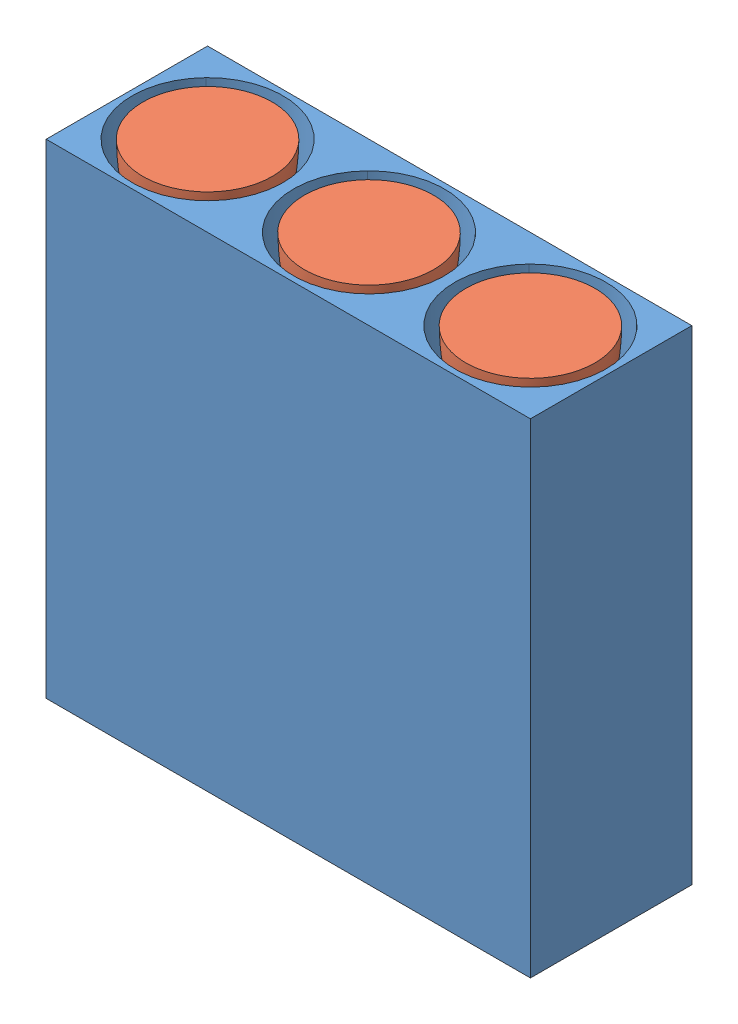
SolidWorks assembly WiderSpace, configuration Default. Lengths in mm.
Overall size (15.49 15 5.52).
4 component instances, 2 part files, 1 mates.
Components (placement in the parent):
- cone_base_tall_wider_gap_seperated_teeth-1: cone_base_tall_wider_gap_seperated_teeth [Default] at origin size (15.49 15 5.52)
- convex_cone-1: convex_cone [Default] at (5 18.1 2.5) x (-1 0 0) z (0 0 1) size (4 15 4)
- convex_cone-2: convex_cone [Default] at (0 18.1 2.5) x (-1 0 0) z (0 0 1) size (4 15 4)
- convex_cone-3: convex_cone [Default] at (-5 18.1 2.5) x (-1 0 0) z (0 0 1) size (4 15 4)
Mates (geometry in assembly coordinates):
- Coincident1: coincident aligned: plane of cone_base_tall-1 through (-7.5 18.1 5) normal (0 1 0); plane of convex_cone-1 through (5 18.1 2.5) normal (0 1 0)
